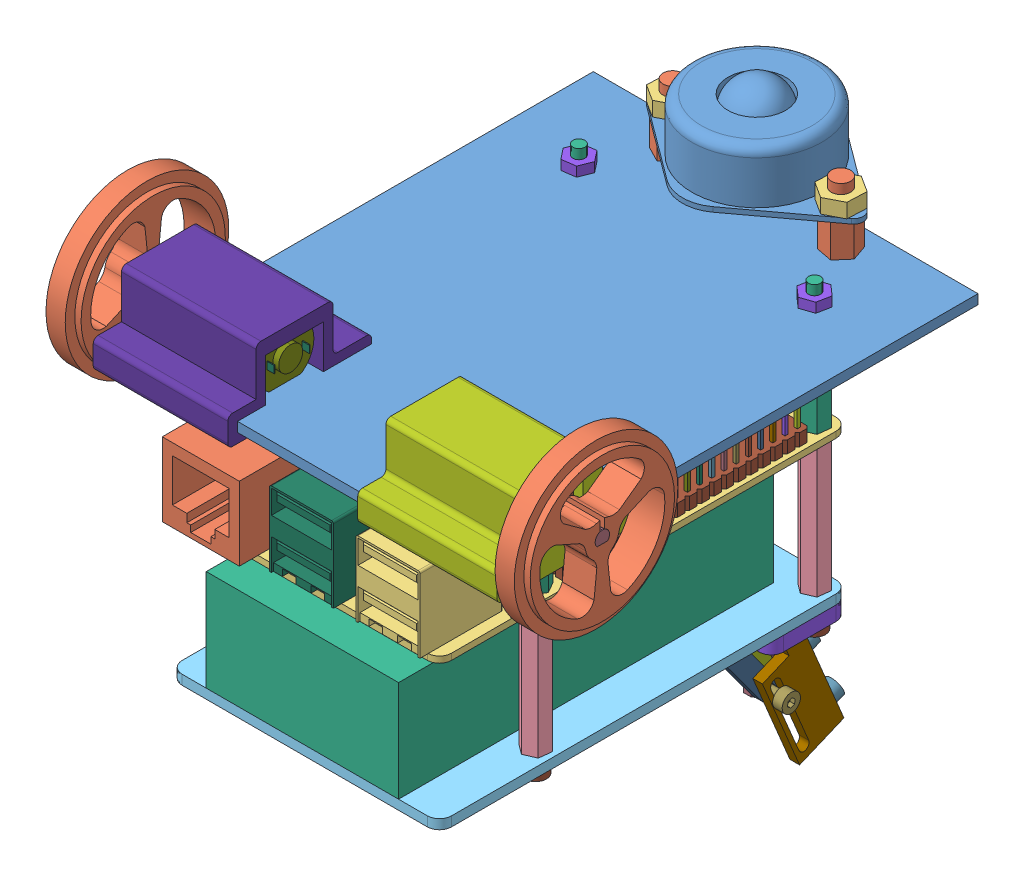
SolidWorks assembly car, configuration 默认. Lengths in mm.
Overall size (100 113.83 114.6).
133 component instances, 86 part files, 157 mates.
Components (placement in the parent):
- car  baseplate-2: car  baseplate [默认] at (1.828 99 14.0699) x (0 0 -1) z (0 1 0) size (100 80 2)
- N20 wheel -1: N20 wheel  [默认] at (51.828 106 52.1949) x (0 0 1) z (0 -1 0) size (34 8.6 34)
- N20 wheel -2: N20 wheel  [默认] at (-48.172 106 52.1949) x (0 0 1) z (0 1 0) size (34 8.6 34)
- raspberrypi3.stp-1: raspberrypi3.stp [默认] at (8.078 86.45 21.5699) x (0 0 1) z (-1 0 0) size (90.89 18.8 58.5)
  - Raspberry Pi 3.stp-1: Raspberry Pi 3.stp [默认] at origin size (90.89 18.8 58.5)
    - Raspberry Pi 3_1.stp-1: Raspberry Pi 3_1.stp [默认] at origin size (85 1.3 56)
    - Raspberry Pi 3_1_1.stp-1: Raspberry Pi 3_1_1.stp [默认] at origin size (14 1 14)
    - Raspberry Pi 3_2.stp-1: Raspberry Pi 3_2.stp [默认] at origin size (8.5 1 8.5)
    - Raspberry Pi 3_3.stp-1: Raspberry Pi 3_3.stp [默认] at origin size (12 1 12)
    - Raspberry Pi 3_4.stp-1: Raspberry Pi 3_4.stp [默认] at origin size (0.64 10.23 0.64)
    - Raspberry Pi 3_5.stp-1: Raspberry Pi 3_5.stp [默认] at origin size (0.64 10.23 0.64)
    - Raspberry Pi 3_6.stp-1: Raspberry Pi 3_6.stp [默认] at origin size (0.64 10.23 0.64)
    - Raspberry Pi 3_7.stp-1: Raspberry Pi 3_7.stp [默认] at origin size (0.64 10.23 0.64)
    - Raspberry Pi 3_8.stp-1: Raspberry Pi 3_8.stp [默认] at origin size (0.64 10.23 0.64)
    - Raspberry Pi 3_9.stp-1: Raspberry Pi 3_9.stp [默认] at origin size (0.64 10.23 0.64)
    - Raspberry Pi 3_10.stp-1: Raspberry Pi 3_10.stp [默认] at origin size (0.64 10.23 0.64)
    - Raspberry Pi 3_11.stp-1: Raspberry Pi 3_11.stp [默认] at origin size (0.64 10.23 0.64)
    - Raspberry Pi 3_12.stp-1: Raspberry Pi 3_12.stp [默认] at origin size (0.64 10.23 0.64)
    - Raspberry Pi 3_13.stp-1: Raspberry Pi 3_13.stp [默认] at origin size (0.64 10.23 0.64)
    - Raspberry Pi 3_14.stp-1: Raspberry Pi 3_14.stp [默认] at origin size (0.64 10.23 0.64)
    - Raspberry Pi 3_15.stp-1: Raspberry Pi 3_15.stp [默认] at origin size (0.64 10.23 0.64)
    - Raspberry Pi 3_16.stp-1: Raspberry Pi 3_16.stp [默认] at origin size (0.64 10.23 0.64)
    - Raspberry Pi 3_17.stp-1: Raspberry Pi 3_17.stp [默认] at origin size (0.64 10.23 0.64)
    - Raspberry Pi 3_18.stp-1: Raspberry Pi 3_18.stp [默认] at origin size (0.64 10.23 0.64)
    - Raspberry Pi 3_19.stp-1: Raspberry Pi 3_19.stp [默认] at origin size (0.64 10.23 0.64)
    - Raspberry Pi 3_20.stp-1: Raspberry Pi 3_20.stp [默认] at origin size (0.64 10.23 0.64)
    - Raspberry Pi 3_21.stp-1: Raspberry Pi 3_21.stp [默认] at origin size (0.64 10.23 0.64)
    - Raspberry Pi 3_22.stp-1: Raspberry Pi 3_22.stp [默认] at origin size (0.64 10.23 0.64)
    - Raspberry Pi 3_23.stp-1: Raspberry Pi 3_23.stp [默认] at origin size (0.64 10.23 0.64)
    - Raspberry Pi 3_24.stp-1: Raspberry Pi 3_24.stp [默认] at origin size (0.64 10.23 0.64)
    - Raspberry Pi 3_25.stp-1: Raspberry Pi 3_25.stp [默认] at origin size (0.64 10.23 0.64)
    - Raspberry Pi 3_26.stp-1: Raspberry Pi 3_26.stp [默认] at origin size (0.64 10.23 0.64)
    - Raspberry Pi 3_27.stp-1: Raspberry Pi 3_27.stp [默认] at origin size (0.64 10.23 0.64)
    - Raspberry Pi 3_28.stp-1: Raspberry Pi 3_28.stp [默认] at origin size (0.64 10.23 0.64)
    - Raspberry Pi 3_29.stp-1: Raspberry Pi 3_29.stp [默认] at origin size (0.64 10.23 0.64)
    - Raspberry Pi 3_30.stp-1: Raspberry Pi 3_30.stp [默认] at origin size (0.64 10.23 0.64)
    - Raspberry Pi 3_31.stp-1: Raspberry Pi 3_31.stp [默认] at origin size (0.64 10.23 0.64)
    - Raspberry Pi 3_32.stp-1: Raspberry Pi 3_32.stp [默认] at origin size (0.64 10.23 0.64)
    - Raspberry Pi 3_33.stp-1: Raspberry Pi 3_33.stp [默认] at origin size (0.64 10.23 0.64)
    - Raspberry Pi 3_34.stp-1: Raspberry Pi 3_34.stp [默认] at origin size (0.64 10.23 0.64)
    - Raspberry Pi 3_35.stp-1: Raspberry Pi 3_35.stp [默认] at origin size (0.64 10.23 0.64)
    - Raspberry Pi 3_36.stp-1: Raspberry Pi 3_36.stp [默认] at origin size (0.64 10.23 0.64)
    - Raspberry Pi 3_37.stp-1: Raspberry Pi 3_37.stp [默认] at origin size (0.64 10.23 0.64)
    - Raspberry Pi 3_38.stp-1: Raspberry Pi 3_38.stp [默认] at origin size (0.64 10.23 0.64)
    - Raspberry Pi 3_39.stp-1: Raspberry Pi 3_39.stp [默认] at origin size (0.64 10.23 0.64)
    - Raspberry Pi 3_40.stp-1: Raspberry Pi 3_40.stp [默认] at origin size (0.64 10.23 0.64)
    - Raspberry Pi 3_41.stp-1: Raspberry Pi 3_41.stp [默认] at origin size (0.64 10.23 0.64)
    - Raspberry Pi 3_42.stp-1: Raspberry Pi 3_42.stp [默认] at origin size (0.64 10.23 0.64)
    - Raspberry Pi 3_43.stp-1: Raspberry Pi 3_43.stp [默认] at origin size (0.64 10.23 0.64)
    - Raspberry Pi 3_44.stp-1: Raspberry Pi 3_44.stp [默认] at origin size (50.8 2.54 5.08)
    - Raspberry Pi 3_45.stp-1: Raspberry Pi 3_45.stp [默认] at origin size (3.91 5.48 22.4)
    - Raspberry Pi 3_46.stp-1: Raspberry Pi 3_46.stp [默认] at origin size (14 1.3 13)
    - Raspberry Pi 3 (micro SD).stp-1: Raspberry Pi 3 (micro SD).stp [默认] at origin size (15 1 11)
    - Raspberry Pi 3_47.stp-1: Raspberry Pi 3_47.stp [默认] at origin size (17.3 15.6 13.3)
    - Raspberry Pi 3_48.stp-1: Raspberry Pi 3_48.stp [默认] at origin size (3.91 5.48 22.4)
    - Raspberry Pi 3_49.stp-1: Raspberry Pi 3_49.stp [默认] at origin size (7.9 2.25 5)
    - Raspberry Pi 3_50.stp-1: Raspberry Pi 3_50.stp [默认] at origin size (15 8.38 11.55)
    - Raspberry Pi 3_51.stp-1: Raspberry Pi 3_51.stp [默认] at origin size (7 9 15)
    - Raspberry Pi 3_52.stp-1: Raspberry Pi 3_52.stp [默认] at origin size (21.4 15.3 16.02)
    - Raspberry Pi 3_53.stp-1: Raspberry Pi 3_53.stp [默认] at origin size (17.3 15.6 13.3)
    - RPi Heatsink Set.stp-1: RPi Heatsink Set.stp [默认] at origin size (14 6 14)
    - RPi Heatsink Set_1.stp-1: RPi Heatsink Set_1.stp [默认] at origin size (8.8 5 8.8)
- M2.5 20+6-1: M2.5 20+6 [默认] at (26.328 79 40.5699) x (0.918342 0 0.395788) z (-0.395788 0 0.918342) size (4.87 26 5.26)
- M2.5 20+6-2: M2.5 20+6 [默认] at (-22.672 79 40.5699) x (0.801933 0 -0.597413) z (0.597413 0 0.801933) size (4.87 26 5.26)
- M2.5 20+6-3: M2.5 20+6 [默认] at (26.328 79 -17.4301) size (4.87 26 5.26)
- M2.5 20+6-4: M2.5 20+6 [默认] at (-22.672 79 -17.4301) size (4.87 26 5.26)
- N20 lift mounting-1: N20 lift mounting [默认] at (41.828 106 52.1949) x (0 0 -1) z (1 0 0) size (29.88 16 29)
- M2.5 nut-1: M2.5 nut [默认] at (26.328 104.5 40.5699) x (0.751714 0 -0.659489) z (0 -1 0) size (5.47 5.66 2)
- M3 8 hexagon socket head cap screw-1: M3 8 hexagon socket head cap screw [默认] at (37.828 94 40.5699) x (0.621977 0 0.783035) z (0 1 0) size (5.5 5.5 11)
- M3 nut-1: M3 nut [默认] at (37.828 104.4 40.5699) x (0.751714 0 -0.659489) z (0 -1 0) size (6.01 6.23 2.4)
- N20 motor-1: N20 motor [默认] at (17.828 106 52.1949) x (0 0 -1) z (0 1 0) size (12 35.5 10)
  - User Library-N20(2)-1: User Library-N20(2) [默认] at origin size (12 35.5 10)
    - User Library-N20_Pad010^User Library-N20(2)-1: User Library-N20_Pad010^User Library-N20(2) [默认] at (0 -23 0) x (1 0 0) z (0 -1 0) size (12 10 2) (virtual)
    - User Library-N20_Pad009^User Library-N20(2)-1: User Library-N20_Pad009^User Library-N20(2) [默认] at (0 -15 0) x (1 0 0) z (0 -1 0) size (12 10 8.5) (virtual)
    - User Library-N20_Pad008-1: User Library-N20_Pad008 [默认] at (0 -1 0) x (1 0 0) z (0 -1 0) size (12 10 33)
    - User Library-N20_Pad006^User Library-N20(2)-1: User Library-N20_Pad006^User Library-N20(2) [默认] at (0 -18 0) x (1 0 0) z (0 -1 0) size (12 10 1) (virtual)
    - User Library-N20_Pad004^User Library-N20(2)-1: User Library-N20_Pad004^User Library-N20(2) [默认] x (1 0 0) z (0 -1 0) size (7.5 1.5 1.5) (virtual)
    - User Library-N20_Pad003^User Library-N20(2)-1: User Library-N20_Pad003^User Library-N20(2) [默认] x (1 0 0) z (0 -1 0) size (12 10 2.2) (virtual)
- N20 motor-2: N20 motor [默认] at (-14.172 106 52.1949) x (0 0 -1) z (0 -1 0) size (12 35.5 10)
  - User Library-N20(2)-1: User Library-N20(2) [默认] at origin size (12 35.5 10)
    - User Library-N20_Pad010^User Library-N20(2)-1: User Library-N20_Pad010^User Library-N20(2) [默认] at (0 -23 0) x (1 0 0) z (0 -1 0) size (12 10 2) (virtual)
    - User Library-N20_Pad009^User Library-N20(2)-1: User Library-N20_Pad009^User Library-N20(2) [默认] at (0 -15 0) x (1 0 0) z (0 -1 0) size (12 10 8.5) (virtual)
    - User Library-N20_Pad008-1: User Library-N20_Pad008 [默认] at (0 -1 0) x (1 0 0) z (0 -1 0) size (12 10 33)
    - User Library-N20_Pad006^User Library-N20(2)-1: User Library-N20_Pad006^User Library-N20(2) [默认] at (0 -18 0) x (1 0 0) z (0 -1 0) size (12 10 1) (virtual)
    - User Library-N20_Pad004^User Library-N20(2)-1: User Library-N20_Pad004^User Library-N20(2) [默认] x (1 0 0) z (0 -1 0) size (7.5 1.5 1.5) (virtual)
    - User Library-N20_Pad003^User Library-N20(2)-1: User Library-N20_Pad003^User Library-N20(2) [默认] x (1 0 0) z (0 -1 0) size (12 10 2.2) (virtual)
- N20 right mounting-1: N20 right mounting [默认] at (-38.172 106 52.1949) x (0 0 -1) z (-1 0 0) size (29.88 16 28)
- M2.5 nut-2: M2.5 nut [默认] at (-22.672 102.5 40.5699) x (-0.946991 0 0.321259) z (0 1 0) size (5.47 5.66 2)
- M3 8 hexagon socket head cap screw-2: M3 8 hexagon socket head cap screw [默认] at (-34.172 94 40.5699) x (-0.837169 0 -0.546944) z (0 1 0) size (5.5 5.5 11)
- M3 nut-2: M3 nut [默认] at (-34.172 104.4 40.5699) x (0.751714 0 -0.659489) z (0 -1 0) size (6.01 6.23 2.4)
- M4 6 hexagon socket head cap screw-1: M4 6 hexagon socket head cap screw [默认] at (-15.672 99 -29.9301) x (-0.837169 0 -0.546944) z (0 -1 0) size (7 7 10)
- ball wheel-1: ball wheel [默认] at (1.828 108 -29.9301) x (0 0 1) z (-1 0 0) size (30.94 15 44.29)
- M4 7+6 copper cylinder-1: M4 7+6 copper cylinder [默认] at (-15.672 101 -29.9301) x (-0.648514 0 -0.761203) z (0 1 0) size (6.41 6.87 13)
- M4 7+6 copper cylinder-2: M4 7+6 copper cylinder [默认] at (19.328 101 -29.9301) x (-0.837169 0 -0.546944) z (0 1 0) size (6.41 6.87 13)
- M4 6 hexagon socket head cap screw-2: M4 6 hexagon socket head cap screw [默认] at (19.328 99 -29.9301) x (-0.837169 0 -0.546944) z (0 -1 0) size (7 7 10)
- M4 nut-1: M4 nut [默认] at (-15.672 112 -29.9301) x (1 0 0) z (0 -1 0) size (7.18 8.07 3)
- M4 nut-2: M4 nut [默认] at (19.328 112 -29.9301) x (1 0 0) z (0 -1 0) size (7.18 8.07 3)
- M2.5 nut-3: M2.5 nut [默认] at (26.328 103 -17.4301) x (1 0 0) z (0 -1 0) size (5.47 5.66 2)
- M2.5 nut-4: M2.5 nut [默认] at (-22.672 101 -17.4301) x (0.837169 0 0.546944) z (0 1 0) size (5.47 5.66 2)
- M2.5 28+6-9: M2.5 28+6 [默认] at (-22.672 49.7 40.5699) x (0.816157 0 -0.57783) z (0.57783 0 0.816157) size (4.87 34 5.26)
- M2.5 28+6-10: M2.5 28+6 [默认] at (26.328 49.7 40.5699) size (4.87 34 5.26)
- M2.5 28+6-11: M2.5 28+6 [默认] at (26.328 49.7 -17.4301) size (4.87 34 5.26)
- M2.5 28+6-12: M2.5 28+6 [默认] at (-22.672 49.7 -17.4301) size (4.87 34 5.26)
- battery pcb-1: battery pcb [默认] at (26.328 49.7 -17.4301) x (-1 0 0) z (0 -1 0) size (56 85 2)
- battery holder-1: battery holder [默认] at (1.328 70.7 25.0699) x (0 0 -1) z (0 -1 0) size (78 40 21)
- camera-1: camera [默认] at (1.828 24.2607 -29.9289) x (-1 0 0) z (0 -0.386222 0.922406) size (25 24 7)
- camera base-1: camera base [默认] at (26.328 47.7 -17.4301) x (-1 0 0) z (0 -1 0) size (56 16 9)
- camera holder 1-1: camera holder 1 [默认] at (26.3313 46.5393 -15.18) x (1 0 0) z (0 -0.386222 0.922406) size (28.99 34.3 10)
- camera holder 2-1: camera holder 2 [默认] at (26.328 44.5296 -2.3483) x (1 0 0) z (0 -0.594827 0.803854) size (24 26.6 4)
- M2.5 8 hexagon socket head cap screw-1: M2.5 8 hexagon socket head cap screw [默认] at (-22.672 44.7 -17.4301) x (1 0 0) z (0 -1 0) size (4.5 4.5 10.5)
- M2.5 8 hexagon socket head cap screw-2: M2.5 8 hexagon socket head cap screw [默认] at (26.328 44.7 -17.4301) x (1 0 0) z (0 -1 0) size (4.5 4.5 10.5)
- M2 8 hexagon socket head cap screw-1: M2 8 hexagon socket head cap screw [默认] at (-12.422 41.7 -6.9301) x (0 0 1) z (-1 0 0) size (3.8 3.8 10)
- M2 8 hexagon socket head cap screw-2: M2 8 hexagon socket head cap screw [默认] at (-14.922 41.7 -18.9301) x (0 0 1) z (-1 0 0) size (3.8 3.8 10)
- M2 8 hexagon socket head cap screw-3: M2 8 hexagon socket head cap screw [默认] at (18.578 41.7 -18.9301) x (0 0.924225 0.381849) z (1 0 0) size (3.8 3.8 10)
- M2 8 hexagon socket head cap screw-4: M2 8 hexagon socket head cap screw [默认] at (16.078 41.7 -6.9301) x (0 0.924225 0.381849) z (1 0 0) size (3.8 3.8 10)
- M2 nut-1: M2 nut [默认] at (12.078 41.7 -18.9301) x (0 0.477612 0.878571) z (-1 0 0) size (4.06 4.62 1.5)
- M2 nut-2: M2 nut [默认] at (-4.422 41.7 -6.9301) x (0 -0.999671 -0.025661) z (-1 0 0) size (4.06 4.62 1.5)
- M2 nut-3: M2 nut [默认] at (-8.422 41.7 -18.9301) x (0 -0.522058 -0.85291) z (1 0 0) size (4.06 4.62 1.5)
- M2 nut-4: M2 nut [默认] at (9.578 41.7 -6.9301) x (0 -0.522058 0.85291) z (-1 0 0) size (4.06 4.62 1.5)
- M2 8 hexagon socket head cap screw-5: M2 8 hexagon socket head cap screw [默认] at (16.328 23.2114 -20.6112) x (0 0.924225 0.381849) z (1 0 0) size (3.8 3.8 10)
- M2 nut-5: M2 nut [默认] at (11.9214 23.2114 -20.6112) x (0 0 1) z (-1 0 0) size (4.06 4.62 1.5)
- M2 nut-7: M2 nut [默认] at (-8.2654 23.2114 -20.6112) x (0 0 -1) z (1 0 0) size (4.06 4.62 1.5)
- M2 8 hexagon socket head cap screw-6: M2 8 hexagon socket head cap screw [默认] at (-12.6654 23.2114 -20.6112) x (0 0 1) z (-1 0 0) size (3.8 3.8 10)
- M2.5 8 hexagon socket head cap screw-3: M2.5 8 hexagon socket head cap screw [默认] at (-22.672 47.7 40.5699) x (0.837169 0 0.546944) z (0 -1 0) size (4.5 4.5 10.5)
- M2.5 8 hexagon socket head cap screw-4: M2.5 8 hexagon socket head cap screw [默认] at (26.328 47.7 40.5699) x (0.837169 0 0.546944) z (0 -1 0) size (4.5 4.5 10.5)
- M2 6 hexagon socket head cap screw-7: M2 6 hexagon socket head cap screw [默认] at (-8.672 15.0367 -33.7911) x (-0.780075 -0.577136 -0.241653) z (0 0.386222 -0.922406) size (3.8 3.8 8)
- M2 6 hexagon socket head cap screw-8: M2 6 hexagon socket head cap screw [默认] at (12.328 15.0367 -33.7911) x (-0.997487 0.065353 0.027364) z (0 0.386222 -0.922406) size (3.8 3.8 8)
- M2 nut-8: M2 nut [默认] at (-8.672 13.878 -31.0239) x (0.477612 -0.810399 -0.339323) z (0 -0.386222 0.922406) size (4.06 4.62 1.5)
- M2 nut-9: M2 nut [默认] at (12.328 13.878 -31.0239) x (0.477612 -0.810399 -0.339323) z (0 -0.386222 0.922406) size (4.06 4.62 1.5)
- M2 6 hexagon socket head cap screw-10: M2 6 hexagon socket head cap screw [默认] at (12.328 27.028 -28.7702) x (-0.997487 0.065353 0.027364) z (0 0.386222 -0.922406) size (3.8 3.8 8)
- M2 6 hexagon socket head cap screw-11: M2 6 hexagon socket head cap screw [默认] at (-8.672 27.028 -28.7702) x (-0.997487 0.065353 0.027364) z (0 0.386222 -0.922406) size (3.8 3.8 8)
- M2 nut-10: M2 nut [默认] at (-8.672 25.8693 -26.003) x (0.522058 0.786729 0.329412) z (0 -0.386222 0.922406) size (4.06 4.62 1.5)
- M2 nut-11: M2 nut [默认] at (12.328 25.8693 -26.003) x (0.477612 -0.810399 -0.339323) z (0 -0.386222 0.922406) size (4.06 4.62 1.5)
Mates (geometry in assembly coordinates):
- 同心8: concentric: cylinder of assembly; cylinder of assembly; cylinder of car  baseplate-2 through (26.328 99 -17.4301) axis (0 1 0) radius 1.35; cylinder of M2.5 20+6-3 through (26.328 105 -17.4301) axis (0 -1 0) radius 1.25
- 同心9: concentric: cylinder of assembly; cylinder of assembly; cylinder of car  baseplate-2 through (-22.672 99 40.5699) axis (0 1 0) radius 1.35; cylinder of M2.5 20+6-2 through (-22.672 105 40.5699) axis (0 -1 0) radius 1.25
- 重合20: coincident: plane of assembly; plane of assembly; plane of car  baseplate-2 through (1.828 99 14.0699) normal (0 -1 0); plane of M2.5 20+6-3 through (26.328 99 -17.4301) normal (0 1 0)
- 平行1: parallel: plane of assembly; plane of assembly; plane of car  baseplate-2 through (-38.172 101 64.0699) normal (0 0 1); plane of M2.5 20+6-1 through (25.003 99 42.8648) normal (0 0 1)
- 平行2: parallel: plane of assembly; plane of assembly; plane of car  baseplate-2 through (-38.172 101 64.0699) normal (0 0 1); plane of M2.5 20+6-2 through (-23.997 99 42.8648) normal (0 0 1)
- 同心11: concentric: cylinder of assembly; cylinder of assembly; cylinder of M2.5 20+6-1 through (26.328 105 40.5699) axis (0 -1 0) radius 1.25; cylinder of M2.5 nut-1 through (26.328 102.5 40.5699) axis (0 1 0) radius 1.25
- 平行4: parallel: plane of assembly; plane of assembly; plane of N20 lift mounting-1 through (24.7403 113 37.8199) normal (0.866025 0 0.5); plane of M2.5 nut-1 through (23.4412 102.5 40.5699) normal (-0.866025 0 -0.5)
- 重合30: coincident: plane of assembly; plane of assembly; plane of N20 lift mounting-1 through (41.828 102.5 52.1949) normal (0 1 0); plane of M2.5 nut-1 through (26.328 102.5 40.5699) normal (0 -1 0)
- 重合31: coincident: plane of assembly; plane of assembly; plane of N20 lift mounting-1 through (43.828 97 52.1949) normal (0 -1 0); plane of M3 8 hexagon socket head cap screw-1 through (37.828 97 40.5699) normal (0 1 0)
- 同心13: concentric: cylinder of assembly; cylinder of assembly; cylinder of M3 8 hexagon socket head cap screw-1 through (37.828 105 40.5699) axis (0 -1 0) radius 1.5; cylinder of M3 nut-1 through (37.828 102 40.5699) axis (0 1 0) radius 1.5
- 平行5: parallel: plane of assembly; plane of assembly; plane of N20 lift mounting-1 through (34.3639 113 40.5699) normal (0.866025 0 -0.5); plane of M3 nut-1 through (36.2403 102 43.3199) normal (-0.866025 0 0.5)
- 同心17: concentric: cylinder of ? through (-22.672 77.7 -17.4301) axis (0 1 0) radius 1.25; cylinder of M2.5 20+6-4 through (-22.672 85 -17.4301) axis (0 -1 0) radius 1.25
- 重合41: coincident: plane of ? through (-26.172 79 21.5699) normal (0 1 0); plane of M2.5 20+6-4 through (-22.672 79 -17.4301) normal (0 -1 0)
- 重合42: coincident: plane of ? through (-26.172 79 21.5699) normal (0 1 0); plane of M2.5 20+6-3 through (26.328 79 -17.4301) normal (0 -1 0)
- 同心18: concentric: cylinder of ? through (26.328 77.7 -17.4301) axis (0 1 0) radius 1.25; cylinder of M2.5 20+6-3 through (26.328 85 -17.4301) axis (0 -1 0) radius 1.25
- 同心19: concentric: cylinder of ? through (26.328 77.7 40.5699) axis (0 1 0) radius 1.25; cylinder of M2.5 20+6-1 through (26.328 85 40.5699) axis (0 -1 0) radius 1.25
- 重合43: coincident: plane of ? through (-26.172 79 21.5699) normal (0 1 0); plane of M2.5 20+6-1 through (26.328 79 40.5699) normal (0 -1 0)
- 同心20: concentric: cylinder of ? through (-22.672 77.7 40.5699) axis (0 1 0) radius 1.25; cylinder of M2.5 20+6-2 through (-22.672 85 40.5699) axis (0 -1 0) radius 1.25
- 重合44: coincident: plane of ? through (-26.172 79 21.5699) normal (0 1 0); plane of M2.5 20+6-2 through (-22.672 79 40.5699) normal (0 -1 0)
- 重合45: coincident: plane of assembly; plane of assembly; plane of N20 lift mounting-1 through (41.828 106 52.1949) normal (-1 0 0); plane of N20 motor-1/User Library-N20(2)-1/User Library-N20_Pad010^User Library-N20(2)-1 through (41.828 101 57.1949) normal (1 0 0)
- 重合46: coincident: plane of assembly; plane of assembly; plane of N20 lift mounting-1 through (-21.0618 106 46.1949) normal (0 0 1); plane of N20 motor-1/User Library-N20(2)-1/User Library-N20_Pad010^User Library-N20(2)-1 through (40.828 102 46.1949) normal (0 0 -1)
- 重合47: coincident: plane of assembly; plane of assembly; plane of car  baseplate-2 through (1.828 101 14.0699) normal (0 1 0); plane of N20 motor-1/User Library-N20(2)-1/User Library-N20_Pad008-1 through (18.828 101 55.5115) normal (0 -1 0)
- 重合48: coincident: plane of assembly; plane of assembly; plane of N20 wheel -1 through (45.228 105 53.3129) normal (0 1 0); plane of N20 motor-1/User Library-N20(2)-1/User Library-N20_Pad008-1 through (43.828 105 52.1949) normal (0 -1 0)
- 同心21: concentric: cylinder of assembly; cylinder of assembly; cylinder of N20 wheel -1 through (45.228 106 52.1949) axis (1 0 0) radius 1.5; cylinder of N20 motor-1/User Library-N20(2)-1/User Library-N20_Pad008-1 through (32.828 106 52.1949) axis (-1 0 0) radius 1.5
- 重合49: coincident: plane of assembly; plane of assembly; plane of N20 wheel -1 through (51.828 106 52.1949) normal (1 0 0); plane of N20 motor-1/User Library-N20(2)-1/User Library-N20_Pad008-1 through (51.828 106 50.6949) normal (1 0 0)
- 重合51: coincident: plane of assembly; plane of assembly; plane of car  baseplate-2 through (1.828 101 14.0699) normal (0 1 0); plane of N20 motor-2/User Library-N20(2)-1/User Library-N20_Pad008-1 through (-15.172 101 48.8782) normal (0 -1 0)
- 平行6: parallel: plane of assembly; plane of assembly; plane of car  baseplate-2 through (-38.172 101 64.0699) normal (0 0 1); plane of N20 motor-2/User Library-N20(2)-1/User Library-N20_Pad010^User Library-N20(2)-1 through (-37.172 102 58.1949) normal (0 0 1)
- 重合54: coincident: plane of assembly; plane of assembly; plane of car  baseplate-2 through (-38.172 101 64.0699) normal (-1 0 0); plane of N20 motor-2/User Library-N20(2)-1/User Library-N20_Pad010^User Library-N20(2)-1 through (-38.172 111 57.1949) normal (-1 0 0)
- 重合55: coincident: plane of assembly; plane of assembly; plane of car  baseplate-2 through (41.828 101 64.0699) normal (1 0 0); plane of N20 motor-1/User Library-N20(2)-1/User Library-N20_Pad010^User Library-N20(2)-1 through (41.828 101 57.1949) normal (1 0 0)
- 距离1: distance = 5.875 mm: plane of assembly; plane of assembly; plane of N20 motor-2/User Library-N20(2)-1/User Library-N20_Pad010^User Library-N20(2)-1 through (-37.172 102 58.1949) normal (0 0 1); plane of car  baseplate-2 through (-38.172 101 64.0699) normal (0 0 1)
- 距离2: distance = 5.875 mm: plane of assembly; plane of assembly; plane of N20 motor-1/User Library-N20(2)-1/User Library-N20_Pad010^User Library-N20(2)-1 through (40.828 110 58.1949) normal (0 0 1); plane of car  baseplate-2 through (-38.172 101 64.0699) normal (0 0 1)
- 重合58: coincident: plane of assembly; plane of assembly; plane of N20 wheel -2 through (-41.572 107 53.3129) normal (0 -1 0); plane of N20 motor-2/User Library-N20(2)-1/User Library-N20_Pad008-1 through (-40.172 107 52.1949) normal (0 1 0)
- 同心22: concentric: cylinder of assembly; cylinder of assembly; cylinder of N20 wheel -2 through (-41.572 106 52.1949) axis (-1 0 0) radius 1.5; cylinder of N20 motor-2/User Library-N20(2)-1/User Library-N20_Pad008-1 through (-29.172 106 52.1949) axis (1 0 0) radius 1.5
- 重合59: coincident: plane of assembly; plane of assembly; plane of N20 wheel -2 through (-48.172 106 52.1949) normal (-1 0 0); plane of N20 motor-2/User Library-N20(2)-1/User Library-N20_Pad008-1 through (-48.172 106 50.6949) normal (-1 0 0)
- 在位1: in place: plane of N20 motor-2/User Library-N20(2)-1/User Library-N20_Pad010^User Library-N20(2)-1 through (-38.172 111 57.1949) normal (-1 0 0); plane of ? through (-38.172 0 0) normal (-1 0 0); moOrthogonalPlaneRef_w of N20 motor-2/User Library-N20(2)-1/User Library-N20_Pad010^User Library-N20(2)-1 through (-38.172 111 57.1949) normal (-1 0 0); plane of ? through (-38.172 0 0) normal (0 1 0); plane of N20 motor-2/User Library-N20(2)-1/User Library-N20_Pad010^User Library-N20(2)-1 through (-38.172 111 57.1949) normal (-1 0 0); plane of ? through (-38.172 0 0) normal (0 0 1); plane of N20 motor-2/User Library-N20(2)-1/User Library-N20_Pad010^User Library-N20(2)-1 through (-38.172 111 57.1949) normal (-1 0 0); unknown of N20 right mounting-1
- 重合60: coincident: plane of assembly; plane of assembly; plane of N20 motor-2/User Library-N20(2)-1/User Library-N20_Pad010^User Library-N20(2)-1; plane of N20 right mounting-1
- 重合61: coincident: plane of assembly; plane of assembly; moOrthogonalPlaneRef_w of N20 motor-2/User Library-N20(2)-1/User Library-N20_Pad010^User Library-N20(2)-1 through (-38.172 106 52.1949) normal (0 -1 0); plane of N20 right mounting-1 through (-38.172 106 52.1949) normal (0 -1 0)
- 重合62: coincident: plane of assembly; plane of assembly; moOrthogonalPlaneRef_w of N20 motor-2/User Library-N20(2)-1/User Library-N20_Pad010^User Library-N20(2)-1 through (-38.172 106 52.1949) normal (0 0 1); plane of N20 right mounting-1 through (-38.172 106 52.1949) normal (0 0 -1)
- 同心23: concentric: cylinder of assembly; cylinder of assembly; cylinder of N20 right mounting-1 through (-34.172 103 40.5699) axis (0 -1 0) radius 1.6; cylinder of M3 8 hexagon socket head cap screw-2 through (-34.172 105 40.5699) axis (0 -1 0) radius 1.5
- 重合63: coincident: plane of assembly; plane of assembly; plane of N20 right mounting-1 through (-40.172 97 52.1949) normal (0 -1 0); plane of M3 8 hexagon socket head cap screw-2 through (-34.172 97 40.5699) normal (0 1 0)
- 同心24: concentric: cylinder of assembly; cylinder of assembly; cylinder of M3 8 hexagon socket head cap screw-2 through (-34.172 105 40.5699) axis (0 -1 0) radius 1.5; cylinder of M3 nut-2 through (-34.172 102 40.5699) axis (0 1 0) radius 1.5
- 平行7: parallel: plane of assembly; plane of assembly; plane of N20 right mounting-1 through (-35.9041 113 37.5699) normal (0.866025 0 0.5); plane of M3 nut-2 through (-37.3475 102 40.5699) normal (-0.866025 0 -0.5)
- 重合65: coincident: plane of assembly; plane of assembly; plane of N20 right mounting-1 through (-38.172 102 52.1949) normal (0 1 0); plane of M3 nut-2 through (-34.172 102 40.5699) normal (0 -1 0)
- 同心25: concentric: cylinder of assembly; cylinder of assembly; cylinder of M2.5 20+6-2 through (-22.672 105 40.5699) axis (0 -1 0) radius 1.25; cylinder of M2.5 nut-2 through (-22.672 104.5 40.5699) axis (0 -1 0) radius 1.25
- 平行8: parallel: plane of assembly; plane of assembly; plane of N20 right mounting-1 through (-24.2597 113 43.3199) normal (0 0 -1); plane of M2.5 nut-2 through (-21.2287 104.5 38.0699) normal (0 0 -1)
- 重合67: coincident: plane of assembly; plane of assembly; plane of N20 right mounting-1 through (-38.172 102.5 52.1949) normal (0 1 0); plane of M2.5 nut-2 through (-22.672 102.5 40.5699) normal (0 -1 0)
- 同心27: concentric: cylinder of assembly; cylinder of assembly; cylinder of ball wheel-1 through (19.328 109 -29.9301) axis (0 -1 0) radius 2; cylinder of M4 7+6 copper cylinder-2 through (19.328 114 -29.9301) axis (0 -1 0) radius 2
- 重合69: coincident: plane of assembly; plane of assembly; plane of ball wheel-1 through (1.828 108 -29.9301) normal (0 -1 0); plane of M4 7+6 copper cylinder-2 through (19.328 108 -29.9301) normal (0 1 0)
- 同心28: concentric: cylinder of assembly; cylinder of assembly; cylinder of car  baseplate-2 through (19.328 91 -29.9301) axis (0 1 0) radius 2.1; cylinder of M4 7+6 copper cylinder-2 through (19.328 105 -29.9301) axis (0 -1 0) radius 2
- 重合70: coincident: plane of assembly; plane of assembly; plane of car  baseplate-2 through (1.828 101 14.0699) normal (0 1 0); plane of M4 7+6 copper cylinder-2 through (19.328 101 -29.9301) normal (0 -1 0)
- 同心32: concentric: cylinder of assembly; cylinder of assembly; cylinder of M4 7+6 copper cylinder-1 through (-15.672 114 -29.9301) axis (0 -1 0) radius 2; cylinder of ball wheel-1 through (-15.672 109 -29.9301) axis (0 -1 0) radius 2
- 重合71: coincident: plane of assembly; plane of assembly; plane of ball wheel-1 through (1.828 108 -29.9301) normal (0 -1 0); plane of M4 7+6 copper cylinder-1 through (-15.672 108 -29.9301) normal (0 1 0)
- 重合72: coincident: plane of assembly; plane of assembly; plane of car  baseplate-2 through (1.828 101 14.0699) normal (0 1 0); plane of M4 7+6 copper cylinder-1 through (-15.672 101 -29.9301) normal (0 -1 0)
- 同心33: concentric: cylinder of assembly; cylinder of assembly; cylinder of M4 6 hexagon socket head cap screw-1 through (-15.672 105 -29.9301) axis (0 -1 0) radius 2; cylinder of M4 7+6 copper cylinder-1 through (-15.672 105 -29.9301) axis (0 -1 0) radius 2
- 重合73: coincident: plane of assembly; plane of assembly; plane of car  baseplate-2 through (1.828 99 14.0699) normal (0 -1 0); plane of M4 6 hexagon socket head cap screw-1 through (-15.672 99 -29.9301) normal (0 1 0)
- 同心34: concentric: cylinder of assembly; cylinder of assembly; cylinder of M4 7+6 copper cylinder-2 through (19.328 105 -29.9301) axis (0 -1 0) radius 2; cylinder of M4 6 hexagon socket head cap screw-2 through (19.328 105 -29.9301) axis (0 -1 0) radius 2
- 重合74: coincident: plane of assembly; plane of assembly; plane of car  baseplate-2 through (1.828 99 14.0699) normal (0 -1 0); plane of M4 6 hexagon socket head cap screw-2 through (19.328 99 -29.9301) normal (0 1 0)
- 同心35: concentric: cylinder of assembly; cylinder of assembly; cylinder of M4 7+6 copper cylinder-1 through (-15.672 114 -29.9301) axis (0 -1 0) radius 2; cylinder of M4 nut-1 through (-15.672 109 -29.9301) axis (0 1 0) radius 2
- 重合75: coincident: plane of assembly; plane of assembly; plane of ball wheel-1 through (1.828 109 -29.9301) normal (0 1 0); plane of M4 nut-1 through (-15.672 109 -29.9301) normal (0 -1 0)
- 同心36: concentric: cylinder of assembly; cylinder of assembly; cylinder of M4 7+6 copper cylinder-2 through (19.328 114 -29.9301) axis (0 -1 0) radius 2; cylinder of M4 nut-2 through (19.328 109 -29.9301) axis (0 1 0) radius 2
- 重合76: coincident: plane of assembly; plane of assembly; plane of ball wheel-1 through (1.828 109 -29.9301) normal (0 1 0); plane of M4 nut-2 through (19.328 109 -29.9301) normal (0 -1 0)
- 同心37: concentric: cylinder of assembly; cylinder of assembly; cylinder of M2.5 20+6-4 through (-22.672 105 -17.4301) axis (0 -1 0) radius 1.25; cylinder of M2.5 nut-4 through (-22.672 103 -17.4301) axis (0 -1 0) radius 1.25
- 重合77: coincident: plane of assembly; plane of assembly; plane of car  baseplate-2 through (1.828 101 14.0699) normal (0 1 0); plane of M2.5 nut-4 through (-22.672 101 -17.4301) normal (0 -1 0)
- 同心38: concentric: cylinder of assembly; cylinder of assembly; cylinder of M2.5 20+6-3 through (26.328 105 -17.4301) axis (0 -1 0) radius 1.25; cylinder of M2.5 nut-3 through (26.328 101 -17.4301) axis (0 1 0) radius 1.25
- 重合78: coincident: plane of assembly; plane of assembly; plane of car  baseplate-2 through (1.828 101 14.0699) normal (0 1 0); plane of M2.5 nut-3 through (26.328 101 -17.4301) normal (0 -1 0)
- 同心39: concentric: cylinder of ? through (-22.672 77.7 40.5699) axis (0 1 0) radius 1.25; cylinder of M2.5 28+6-9 through (-22.672 83.7 40.5699) axis (0 -1 0) radius 1.25
- 重合79: coincident: plane of ? through (1.828 77.7 -20.9301) normal (0 -1 0); plane of M2.5 28+6-9 through (-22.672 77.7 40.5699) normal (0 1 0)
- 同心40: concentric: cylinder of assembly; cylinder of assembly; cylinder of M2.5 20+6-3 through (26.328 85 -17.4301) axis (0 -1 0) radius 1.25; cylinder of M2.5 28+6-11 through (26.328 83.7 -17.4301) axis (0 -1 0) radius 1.25
- 重合80: coincident: plane of ? through (1.828 77.7 -20.9301) normal (0 -1 0); plane of M2.5 28+6-11 through (26.328 77.7 -17.4301) normal (0 1 0)
- 同心41: concentric: cylinder of assembly; cylinder of assembly; cylinder of M2.5 20+6-1 through (26.328 85 40.5699) axis (0 -1 0) radius 1.25; cylinder of M2.5 28+6-10 through (26.328 83.7 40.5699) axis (0 -1 0) radius 1.25
- 重合81: coincident: plane of ? through (1.828 77.7 -20.9301) normal (0 -1 0); plane of M2.5 28+6-10 through (26.328 77.7 40.5699) normal (0 1 0)
- 同心42: concentric: cylinder of assembly; cylinder of assembly; cylinder of M2.5 20+6-4 through (-22.672 85 -17.4301) axis (0 -1 0) radius 1.25; cylinder of M2.5 28+6-12 through (-22.672 83.7 -17.4301) axis (0 -1 0) radius 1.25
- 重合82: coincident: plane of ? through (1.828 77.7 -20.9301) normal (0 -1 0); plane of M2.5 28+6-12 through (-22.672 77.7 -17.4301) normal (0 1 0)
- 在位2: in place: plane of ? through (26.328 57.7 -17.4301) normal (0 -1 0); plane of ? through (0 57.7 0) normal (0 -1 0); plane of ? through (26.328 57.7 -17.4301) normal (0 -1 0); plane of ? through (0 57.7 0) normal (0 0 -1); plane of ? through (26.328 57.7 -17.4301) normal (0 -1 0); plane of ? through (0 57.7 0) normal (-1 0 0); plane of M2.5 28+6-11 through (26.328 49.7 -17.4301) normal (0 -1 0); unknown of battery pcb-1
- 重合83: coincident: plane of assembly; plane of assembly; plane of M2.5 28+6-11; plane of battery pcb-1
- 重合84: coincident: plane of assembly; plane of assembly; moOrthogonalPlaneRef_w of M2.5 28+6-11 through (26.328 49.7 -17.4301) normal (0 0 -1); plane of battery pcb-1 through (26.328 49.7 -17.4301) normal (0 0 -1)
- 重合85: coincident: plane of assembly; plane of assembly; moOrthogonalPlaneRef_w of M2.5 28+6-11 through (26.328 49.7 -17.4301) normal (1 0 0); plane of battery pcb-1 through (26.328 49.7 -17.4301) normal (-1 0 0)
- 同心43: concentric: cylinder of assembly; cylinder of assembly; cylinder of M2.5 28+6-9 through (-22.672 55.7 40.5699) axis (0 -1 0) radius 1.25; cylinder of battery pcb-1 through (-22.672 47.7 40.5699) axis (0 1 0) radius 1.3
- 重合92: coincident: plane of assembly; plane of assembly; plane of battery pcb-1 through (27.328 49.7 61.5699) normal (0 1 0); plane of battery holder-1 through (1.328 49.7 25.0699) normal (0 -1 0)
- 重合93: coincident: plane of battery pcb-1 through (27.328 47.7 64.0699) normal (0 0 1); plane of battery holder-1 through (21.328 49.7 64.0699) normal (0 0 1)
- 距离4: distance = 7.5 mm: plane of battery holder-1 through (-18.672 49.7 64.0699) normal (-1 0 0); plane of battery pcb-1 through (-26.172 47.7 -18.4301) normal (-1 0 0)
- 在位5: in place: plane of battery pcb-1 through (27.328 47.7 61.5699) normal (0 -1 0); plane of ? through (0 47.7 0) normal (0 -1 0); plane of battery pcb-1 through (27.328 47.7 61.5699) normal (0 -1 0); plane of ? through (0 47.7 0) normal (0 0 -1); plane of battery pcb-1 through (27.328 47.7 61.5699) normal (0 -1 0); plane of ? through (0 47.7 0) normal (-1 0 0); plane of battery pcb-1 through (27.328 47.7 61.5699) normal (0 -1 0); unknown of camera base-1
- 重合101: coincident: plane of assembly; plane of assembly; plane of battery pcb-1; plane of camera base-1
- 重合102: coincident: plane of assembly; plane of assembly; moOrthogonalPlaneRef_w of battery pcb-1 through (26.328 47.7 -17.4301) normal (0 0 -1); plane of camera base-1 through (26.328 47.7 -17.4301) normal (0 0 -1)
- 重合103: coincident: plane of assembly; plane of assembly; moOrthogonalPlaneRef_w of battery pcb-1 through (26.328 47.7 -17.4301) normal (1 0 0); plane of camera base-1 through (26.328 47.7 -17.4301) normal (-1 0 0)
- 同心48: concentric: cylinder of assembly; cylinder of assembly; cylinder of camera base-1 through (-26.172 41.7 -18.9301) axis (1 0 0) radius 1.1; cylinder of camera holder 1-1 through (-12.6654 41.7 -18.9301) axis (1 0 0) radius 1
- 同心49: concentric: cylinder of assembly; cylinder of assembly; cylinder of camera base-1 through (-26.172 41.7 -18.9301) axis (1 0 0) radius 1.1; cylinder of camera holder 1-1 through (-12.6654 41.7 -18.9301) axis (1 0 0) radius 1
- 同心50: concentric: cylinder of assembly; cylinder of assembly; cylinder of camera base-1 through (-26.172 41.7 -6.9301) axis (1 0 0) radius 1.1; cylinder of camera holder 2-1 through (-10.172 41.7 -6.9301) axis (1 0 0) radius 1.1
- 同心51: concentric: cylinder of camera base-1 through (-26.172 41.7 -6.9301) axis (1 0 0) radius 1.1; cylinder of camera holder 2-1 through (-10.172 41.7 -6.9301) axis (1 0 0) radius 1.1
- 平行12: parallel: plane of camera holder 1-1 through (14.328 45.3169 -20.0283) normal (-1 0 0); plane of camera holder 2-1 through (13.828 46.9089 -5.5637) normal (1 0 0)
- 相切1: tangent: plane of camera holder 1-1 through (-12.6654 45.4192 -12.505) normal (0 -0.386222 0.922406); cylinder of camera holder 2-1 through (-10.172 23.2114 -20.6112) axis (1 0 0) radius 1.1
- 距离6: distance = 0.25 mm: plane of camera holder 2-1 through (13.828 46.9089 -5.5637) normal (1 0 0); plane of camera base-1 through (14.078 38.7 -17.4301) normal (-1 0 0)
- 距离7: distance = 0.25 mm: plane of assembly; plane of assembly; plane of camera holder 1-1 through (14.328 45.3169 -20.0283) normal (-1 0 0); plane of camera base-1 through (14.078 38.7 -17.4301) normal (1 0 0)
- LimitDistance1: limit distance = 0.9154 mm: cylinder of camera holder 2-1 through (-10.172 23.2114 -20.6112) axis (1 0 0) radius 1.1; cylinder of camera holder 1-1 through (-12.6654 26.085 -19.4079) axis (1 0 0) radius 1.1
- 同心52: concentric: cylinder of assembly; cylinder of assembly; cylinder of camera base-1 through (26.328 44.7 -17.4301) axis (0 1 0) radius 1.3; cylinder of M2.5 8 hexagon socket head cap screw-2 through (26.328 52.7 -17.4301) axis (0 -1 0) radius 1.25
- 重合113: coincident: plane of camera base-1 through (26.328 44.7 -17.4301) normal (0 -1 0); plane of M2.5 8 hexagon socket head cap screw-2 through (26.328 44.7 -17.4301) normal (0 1 0)
- 同心53: concentric: cylinder of assembly; cylinder of assembly; cylinder of camera base-1 through (-22.672 44.7 -17.4301) axis (0 1 0) radius 1.3; cylinder of M2.5 8 hexagon socket head cap screw-1 through (-22.672 52.7 -17.4301) axis (0 -1 0) radius 1.25
- 重合114: coincident: plane of camera base-1 through (26.328 44.7 -17.4301) normal (0 -1 0); plane of M2.5 8 hexagon socket head cap screw-1 through (-22.672 44.7 -17.4301) normal (0 1 0)
- 同心54: concentric: cylinder of assembly; cylinder of assembly; cylinder of camera holder 1-1 through (-12.6654 41.7 -18.9301) axis (1 0 0) radius 1; cylinder of M2 8 hexagon socket head cap screw-3 through (10.578 41.7 -18.9301) axis (1 0 0) radius 1
- 重合115: coincident: plane of camera base-1 through (18.578 38.7 -17.4301) normal (1 0 0); plane of M2 8 hexagon socket head cap screw-3 through (18.578 41.7 -18.9301) normal (-1 0 0)
- 同心55: concentric: cylinder of M2 8 hexagon socket head cap screw-3 through (10.578 41.7 -18.9301) axis (1 0 0) radius 1; cylinder of M2 nut-1 through (12.578 41.7 -18.9301) axis (-1 0 0) radius 1
- 重合116: coincident: plane of camera base-1 through (12.078 38.7 -17.4301) normal (-1 0 0); plane of M2 nut-1 through (12.078 41.7 -18.9301) normal (1 0 0)
- 平行13: parallel: plane of camera base-1 through (26.328 44.7 -17.4301) normal (0 -1 0); plane of M2 nut-1 through (10.578 39.7 -20.0848) normal (0 -1 0)
- 同心56: concentric: cylinder of assembly; cylinder of assembly; cylinder of camera holder 1-1 through (-12.6654 41.7 -18.9301) axis (1 0 0) radius 1; cylinder of M2 8 hexagon socket head cap screw-2 through (-6.922 41.7 -18.9301) axis (-1 0 0) radius 1
- 重合118: coincident: plane of camera base-1 through (-14.922 38.7 -17.4301) normal (-1 0 0); plane of M2 8 hexagon socket head cap screw-2 through (-14.922 41.7 -18.9301) normal (1 0 0)
- 同心57: concentric: cylinder of M2 8 hexagon socket head cap screw-2 through (-6.922 41.7 -18.9301) axis (-1 0 0) radius 1; cylinder of M2 nut-3 through (-8.922 41.7 -18.9301) axis (1 0 0) radius 1
- 重合119: coincident: plane of camera base-1 through (-8.422 38.7 -17.4301) normal (1 0 0); plane of M2 nut-3 through (-8.422 41.7 -18.9301) normal (-1 0 0)
- 平行14: parallel: plane of camera base-1 through (26.328 44.7 -17.4301) normal (0 -1 0); plane of M2 nut-3 through (-6.922 39.7 -17.7754) normal (0 -1 0)
- 同心58: concentric: cylinder of camera holder 2-1 through (-10.172 41.7 -6.9301) axis (1 0 0) radius 1.1; cylinder of M2 8 hexagon socket head cap screw-1 through (-4.422 41.7 -6.9301) axis (-1 0 0) radius 1
- 重合121: coincident: plane of camera base-1 through (-12.422 38.7 -17.4301) normal (-1 0 0); plane of M2 8 hexagon socket head cap screw-1 through (-12.422 41.7 -6.9301) normal (1 0 0)
- 同心59: concentric: cylinder of M2 8 hexagon socket head cap screw-1 through (-4.422 41.7 -6.9301) axis (-1 0 0) radius 1; cylinder of M2 nut-2 through (-3.922 41.7 -6.9301) axis (-1 0 0) radius 1
- 重合122: coincident: plane of camera base-1 through (-5.922 38.7 -17.4301) normal (1 0 0); plane of M2 nut-2 through (-5.922 41.7 -6.9301) normal (-1 0 0)
- 同心60: concentric: cylinder of camera holder 2-1 through (-10.172 41.7 -6.9301) axis (1 0 0) radius 1.1; cylinder of M2 8 hexagon socket head cap screw-4 through (8.078 41.7 -6.9301) axis (1 0 0) radius 1
- 重合123: coincident: plane of camera base-1 through (16.078 38.7 -17.4301) normal (1 0 0); plane of M2 8 hexagon socket head cap screw-4 through (16.078 41.7 -6.9301) normal (-1 0 0)
- 同心61: concentric: cylinder of M2 8 hexagon socket head cap screw-4 through (8.078 41.7 -6.9301) axis (1 0 0) radius 1; cylinder of M2 nut-4 through (10.078 41.7 -6.9301) axis (-1 0 0) radius 1
- 重合124: coincident: plane of camera base-1 through (9.578 38.7 -17.4301) normal (-1 0 0); plane of M2 nut-4 through (9.578 41.7 -6.9301) normal (1 0 0)
- 平行15: parallel: plane of camera base-1 through (26.328 44.7 -17.4301) normal (0 -1 0); plane of M2 nut-4 through (8.078 39.7 -8.0848) normal (0 -1 0)
- 平行16: parallel: plane of camera base-1 through (26.328 44.7 -17.4301) normal (0 -1 0); plane of M2 nut-2 through (-5.922 39.7 -8.0848) normal (0 -1 0)
- 同心62: concentric: cylinder of camera holder 2-1 through (-10.172 23.2114 -20.6112) axis (1 0 0) radius 1.1; cylinder of M2 8 hexagon socket head cap screw-5 through (8.328 23.2114 -20.6112) axis (1 0 0) radius 1
- 重合127: coincident: plane of camera holder 1-1 through (16.328 45.3169 -20.0283) normal (1 0 0); plane of M2 8 hexagon socket head cap screw-5 through (16.328 23.2114 -20.6112) normal (-1 0 0)
- 同心63: concentric: cylinder of M2 8 hexagon socket head cap screw-5 through (8.328 23.2114 -20.6112) axis (1 0 0) radius 1; cylinder of M2 nut-5 through (12.4214 23.2114 -20.6112) axis (-1 0 0) radius 1
- 重合128: coincident: plane of camera holder 2-1 through (11.9214 46.9089 -5.5637) normal (-1 0 0); plane of M2 nut-5 through (11.9214 23.2114 -20.6112) normal (1 0 0)
- 同心64: concentric: cylinder of camera holder 2-1 through (-10.172 23.2114 -20.6112) axis (1 0 0) radius 1.1; cylinder of M2 8 hexagon socket head cap screw-6 through (-4.6654 23.2114 -20.6112) axis (-1 0 0) radius 1
- 重合129: coincident: plane of camera holder 1-1 through (-12.6654 45.3169 -20.0283) normal (-1 0 0); plane of M2 8 hexagon socket head cap screw-6 through (-12.6654 23.2114 -20.6112) normal (1 0 0)
- 同心65: concentric: cylinder of M2 nut-7 through (-8.7654 23.2114 -20.6112) axis (1 0 0) radius 1; cylinder of M2 8 hexagon socket head cap screw-6 through (-4.6654 23.2114 -20.6112) axis (-1 0 0) radius 1
- 重合130: coincident: plane of camera holder 2-1 through (-8.2654 46.9089 -5.5637) normal (1 0 0); plane of M2 nut-7 through (-8.2654 23.2114 -20.6112) normal (-1 0 0)
- 同心66: concentric: cylinder of assembly; cylinder of assembly; cylinder of M2.5 28+6-10 through (26.328 55.7 40.5699) axis (0 -1 0) radius 1.25; cylinder of M2.5 8 hexagon socket head cap screw-4 through (26.328 55.7 40.5699) axis (0 -1 0) radius 1.25
- 重合131: coincident: plane of battery pcb-1 through (27.328 47.7 61.5699) normal (0 -1 0); plane of M2.5 8 hexagon socket head cap screw-4 through (26.328 47.7 40.5699) normal (0 1 0)
- 同心67: concentric: cylinder of assembly; cylinder of assembly; cylinder of M2.5 28+6-9 through (-22.672 55.7 40.5699) axis (0 -1 0) radius 1.25; cylinder of M2.5 8 hexagon socket head cap screw-3 through (-22.672 55.7 40.5699) axis (0 -1 0) radius 1.25
- 重合132: coincident: plane of battery pcb-1 through (27.328 47.7 61.5699) normal (0 -1 0); plane of M2.5 8 hexagon socket head cap screw-3 through (-22.672 47.7 40.5699) normal (0 1 0)
- 重合133: coincident: plane of assembly; plane of assembly; plane of car  baseplate-2 through (1.828 99 14.0699) normal (0 -1 0); plane of N20 lift mounting-1 through (-21.0618 99 52.1949) normal (0 1 0)
- 同心68: concentric: cylinder of assembly; cylinder of assembly; cylinder of car  baseplate-2 through (37.828 101 40.5699) axis (0 -1 0) radius 1.6; cylinder of M3 8 hexagon socket head cap screw-1 through (37.828 105 40.5699) axis (0 -1 0) radius 1.5
- 重合135: coincident: plane of assembly; plane of assembly; plane of N20 lift mounting-1 through (41.828 102 52.1949) normal (0 1 0); plane of M3 nut-1 through (37.828 102 40.5699) normal (0 -1 0)
- 重合136: coincident: plane of assembly; plane of assembly; plane of camera-1 through (1.828 23.8745 -29.0065) normal (0 -0.386222 0.922406); plane of camera holder 1-1 through (26.3313 48.0841 -18.8696) normal (0 0.386222 -0.922406)
- 重合137: coincident: plane of camera-1 through (1.828 23.8745 -29.0065) normal (0 -0.386222 0.922406); plane of camera holder 1-1 through (26.3313 48.0841 -18.8696) normal (0 0.386222 -0.922406)
- 同心69: concentric: cylinder of camera-1 through (12.328 14.6505 -32.8687) axis (0 0.386222 -0.922406) radius 1.1; cylinder of camera holder 1-1 through (12.328 13.878 -31.0239) axis (0 0.386222 -0.922406) radius 1
- 平行18: parallel: plane of camera-1 through (14.328 12.8056 -33.6411) normal (0 -0.922406 -0.386222); plane of camera holder 1-1 through (-12.6654 13.0327 -33.546) normal (0 -0.922406 -0.386222)
- 同心71: concentric: cylinder of camera-1 through (-8.672 14.6505 -32.8687) axis (0 0.386222 -0.922406) radius 1.1; cylinder of M2 6 hexagon socket head cap screw-7 through (-8.672 12.7194 -28.2567) axis (0 0.386222 -0.922406) radius 1
- 重合139: coincident: plane of camera-1 through (1.828 24.2607 -29.9289) normal (0 0.386222 -0.922406); plane of M2 6 hexagon socket head cap screw-7 through (-8.672 15.0367 -33.7911) normal (0 -0.386222 0.922406)
- 同心72: concentric: cylinder of M2 6 hexagon socket head cap screw-7 through (-8.672 12.7194 -28.2567) axis (0 0.386222 -0.922406) radius 1; cylinder of M2 nut-8 through (-8.672 14.0711 -31.4851) axis (0 -0.386222 0.922406) radius 1
- 重合140: coincident: plane of camera holder 1-1 through (26.3313 47.3117 -17.0248) normal (0 -0.386222 0.922406); plane of M2 nut-8 through (-8.672 13.878 -31.0239) normal (0 0.386222 -0.922406)
- 平行19: parallel: plane of camera holder 1-1 through (-10.6654 45.3169 -20.0283) normal (1 0 0); plane of M2 nut-8 through (-10.672 14.3638 -29.1943) normal (-1 0 0)
- 同心73: concentric: cylinder of camera-1 through (12.328 14.6505 -32.8687) axis (0 0.386222 -0.922406) radius 1.1; cylinder of M2 6 hexagon socket head cap screw-8 through (12.328 12.7194 -28.2567) axis (0 0.386222 -0.922406) radius 1
- 重合142: coincident: plane of camera-1 through (1.828 24.2607 -29.9289) normal (0 0.386222 -0.922406); plane of M2 6 hexagon socket head cap screw-8 through (12.328 15.0367 -33.7911) normal (0 -0.386222 0.922406)
- 同心74: concentric: cylinder of M2 6 hexagon socket head cap screw-8 through (12.328 12.7194 -28.2567) axis (0 0.386222 -0.922406) radius 1; cylinder of M2 nut-9 through (12.328 14.0711 -31.4851) axis (0 -0.386222 0.922406) radius 1
- 重合143: coincident: plane of camera holder 1-1 through (26.3313 47.3117 -17.0248) normal (0 -0.386222 0.922406); plane of M2 nut-9 through (12.328 13.878 -31.0239) normal (0 0.386222 -0.922406)
- 平行20: parallel: plane of camera holder 1-1 through (14.328 45.3169 -20.0283) normal (-1 0 0); plane of M2 nut-9 through (10.328 14.3638 -29.1943) normal (-1 0 0)
- 同心75: concentric: cylinder of camera-1 through (-8.672 26.6417 -27.8478) axis (0 0.386222 -0.922406) radius 1.1; cylinder of M2 6 hexagon socket head cap screw-11 through (-8.672 24.7106 -23.2358) axis (0 0.386222 -0.922406) radius 1
- 重合145: coincident: plane of camera-1 through (1.828 24.2607 -29.9289) normal (0 0.386222 -0.922406); plane of M2 6 hexagon socket head cap screw-11 through (-8.672 27.028 -28.7702) normal (0 -0.386222 0.922406)
- 同心76: concentric: cylinder of camera-1 through (12.328 26.6417 -27.8478) axis (0 0.386222 -0.922406) radius 1.1; cylinder of M2 6 hexagon socket head cap screw-10 through (12.328 24.7106 -23.2358) axis (0 0.386222 -0.922406) radius 1
- 重合146: coincident: plane of camera-1 through (1.828 24.2607 -29.9289) normal (0 0.386222 -0.922406); plane of M2 6 hexagon socket head cap screw-10 through (12.328 27.028 -28.7702) normal (0 -0.386222 0.922406)
- 同心77: concentric: cylinder of M2 6 hexagon socket head cap screw-11 through (-8.672 24.7106 -23.2358) axis (0 0.386222 -0.922406) radius 1; cylinder of M2 nut-10 through (-8.672 26.0624 -26.4642) axis (0 -0.386222 0.922406) radius 1
- 重合147: coincident: plane of assembly; plane of assembly; plane of camera holder 1-1 through (26.3313 47.3117 -17.0248) normal (0 -0.386222 0.922406); plane of M2 nut-10 through (-8.672 25.8693 -26.003) normal (0 0.386222 -0.922406)
- 平行21: parallel: plane of assembly; plane of assembly; plane of camera holder 1-1 through (-10.6654 45.3169 -20.0283) normal (1 0 0); plane of M2 nut-10 through (-6.672 24.2249 -25.0653) normal (1 0 0)
- 同心78: concentric: cylinder of M2 6 hexagon socket head cap screw-10 through (12.328 24.7106 -23.2358) axis (0 0.386222 -0.922406) radius 1; cylinder of M2 nut-11 through (12.328 26.0624 -26.4642) axis (0 -0.386222 0.922406) radius 1
- 重合149: coincident: plane of assembly; plane of assembly; plane of camera holder 1-1 through (26.3313 47.3117 -17.0248) normal (0 -0.386222 0.922406); plane of M2 nut-11 through (12.328 25.8693 -26.003) normal (0 0.386222 -0.922406)
- 平行22: parallel: plane of assembly; plane of assembly; plane of camera holder 1-1 through (14.328 45.3169 -20.0283) normal (-1 0 0); plane of M2 nut-11 through (10.328 26.3551 -24.1734) normal (-1 0 0)
